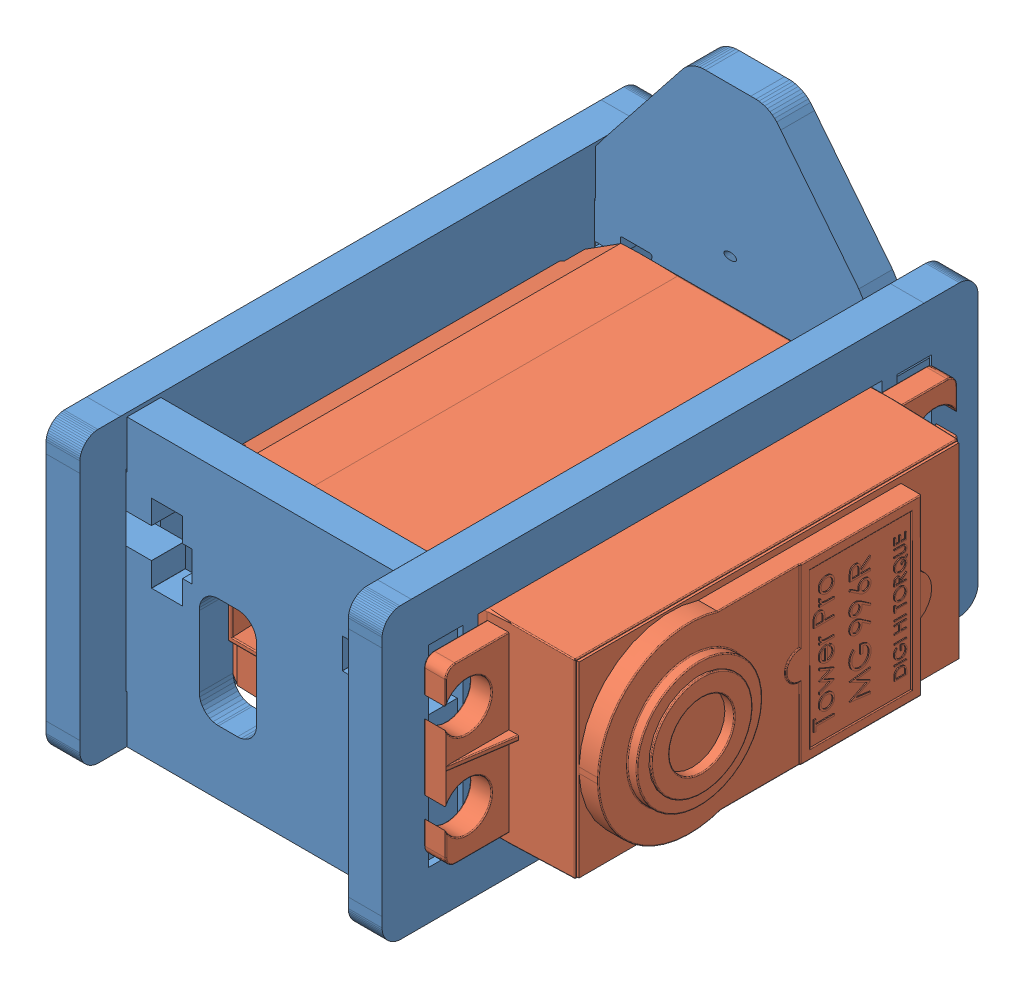
SolidWorks assembly Assem2, configuration Default. Lengths in mm.
Overall size (47.35 55.01 61.78).
4 component instances, 3 part files, 2 mates.
Components (placement in the parent):
- neck_100-1: neck_100 [Default] at origin size (34.84 55.01 61.78)
- main_assembly-1: main_assembly [Default] at (-23.8059 12.4602 -8.1706) x (-0.0005 1 0) z (1 0.0005 0) size (20 53 41.5)
  - main_body-1: main_body [Default] at (15.1003 34.2066 38.7045) size (20 53 41.5)
- hs-422_horn_2wings_sws-1: hs-422_horn_2wings_sws [Default] at (17.5364 27.208 -2.0595) x (-0.999992 0.003972 0) z (0.003972 0.999992 0) size (9.1 5 34)
Mates (geometry in assembly coordinates):
- Coincident1: coincident anti-aligned: line of neck_100-1 through (34.886 37.5898 46.9445) axis (0 0 -1); line of main_assembly-1/main_body-1 through (34.886 37.5898 6.2859) axis (0 0 1)
- ProfileCenter1: profile center anti-aligned: circle of neck_100-1; circle of hs-422_horn_2wings_sws-1
